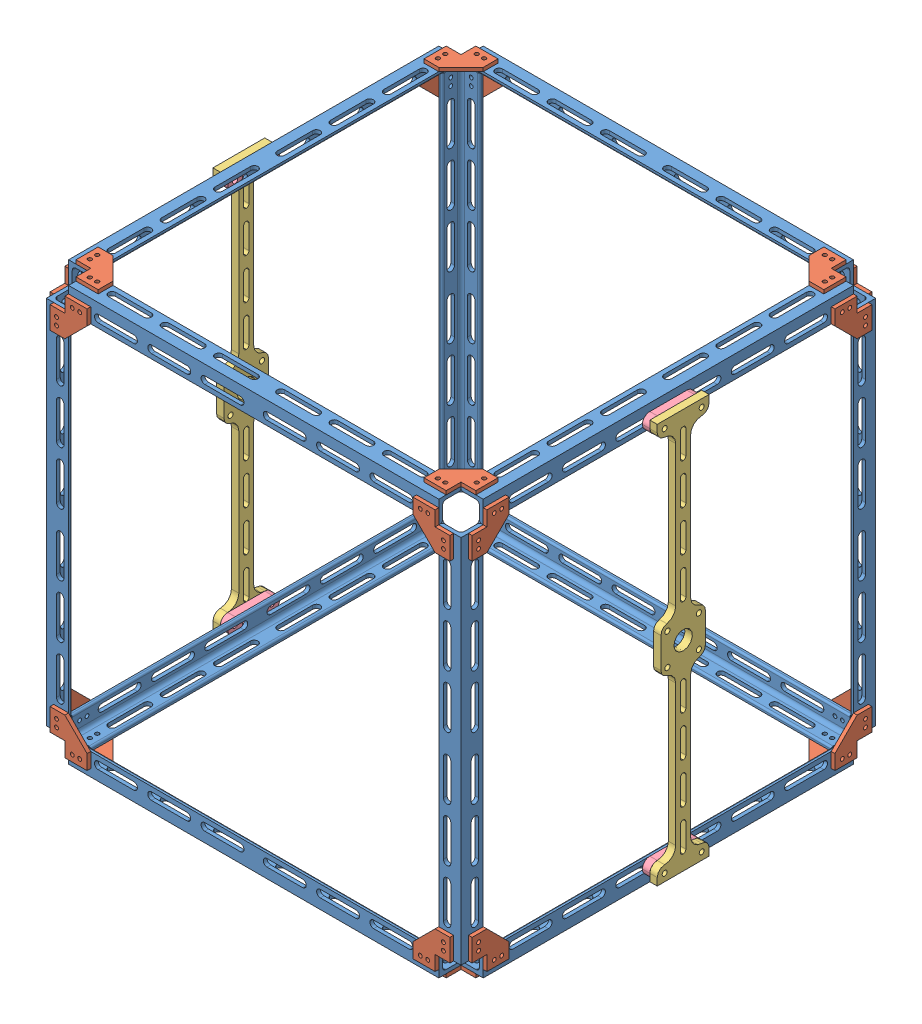
SolidWorks assembly Sattelite_BearingCrossbeams, configuration Default. Lengths in mm.
Overall size (381 361.95 361.95).
43 component instances, 4 part files, 6 mates.
Components (placement in the parent):
- Outer struct 14 in side length-1: Outer struct 14 in side length [Default] at (177.8 -177.8 0) size (361.95 361.95 361.95)
  - WIP 14 inch .75 L rod-1: WIP 14 inch .75 L rod [8982K281] at (-9.525 9.525 0) size (19.05 19.05 317.5)
  - WIP bracket for .75 L bar-1: WIP bracket for .75 L bar [Default] at (-44.45 -3.175 -171.45) size (31.75 3.17 31.75)
  - WIP 14 inch .75 L rod-2: WIP 14 inch .75 L rod [8982K281] at (-177.8 9.525 -168.275) x (0 0 -1) z (1 0 0) size (19.05 19.05 317.5)
  - WIP 14 inch .75 L rod-3: WIP 14 inch .75 L rod [8982K281] at (-9.525 177.8 -168.275) x (1 0 0) z (0 -1 0) size (19.05 19.05 317.5)
  - WIP bracket for .75 L bar-2: WIP bracket for .75 L bar [Default] at (0 44.45 -171.45) x (0 -1 0) z (0 0 1) size (31.75 3.17 31.75)
  - WIP bracket for .75 L bar-3: WIP bracket for .75 L bar [Default] at (-44.45 6.35 -177.8) x (1 0 0) z (0 1 0) size (31.75 3.17 31.75)
  - WIP bracket for .75 L bar-4: WIP bracket for .75 L bar [Default] at (-311.15 349.25 -177.8) x (-1 0 0) z (0 -1 0) size (31.75 3.17 31.75)
  - WIP bracket for .75 L bar-5: WIP bracket for .75 L bar [Default] at (-355.6 311.15 -171.45) x (0 1 0) z (0 0 1) size (31.75 3.17 31.75)
  - WIP bracket for .75 L bar-6: WIP bracket for .75 L bar [Default] at (-311.15 358.775 -171.45) x (-1 0 0) z (0 0 1) size (31.75 3.17 31.75)
  - WIP 14 inch .75 L rod-4: WIP 14 inch .75 L rod [8982K281] at (-177.8 346.075 -168.275) x (0 0 -1) z (-1 0 0) size (19.05 19.05 317.5)
  - WIP 14 inch .75 L rod-5: WIP 14 inch .75 L rod [8982K281] at (-346.075 346.075 0) x (-1 0 0) z (0 0 1) size (19.05 19.05 317.5)
  - WIP 14 inch .75 L rod-6: WIP 14 inch .75 L rod [8982K281] at (-346.075 177.8 -168.275) x (-1 0 0) z (0 1 0) size (19.05 19.05 317.5)
  - WIP bracket for .75 L bar-8: WIP bracket for .75 L bar [Default] at (-6.35 311.15 -177.8) x (0 1 0) z (-1 0 0) size (31.75 3.17 31.75)
  - WIP bracket for .75 L bar-9: WIP bracket for .75 L bar [Default] at (-349.25 44.45 -177.8) x (0 -1 0) z (1 0 0) size (31.75 3.17 31.75)
  - WIP bracket for .75 L bar-11: WIP bracket for .75 L bar [Default] at (-6.35 355.6 133.35) x (0 0 1) z (-1 0 0) size (31.75 3.17 31.75)
  - WIP bracket for .75 L bar-12: WIP bracket for .75 L bar [Default] at (-44.45 349.25 177.8) x (1 0 0) z (0 -1 0) size (31.75 3.17 31.75)
  - WIP 14 inch .75 L rod-7: WIP 14 inch .75 L rod [8982K281] at (-177.8 346.075 168.275) x (0 0 1) z (1 0 0) size (19.05 19.05 317.5)
  - WIP 14 inch .75 L rod-8: WIP 14 inch .75 L rod [8982K281] at (-9.525 346.075 0) x (0 1 0) z (0 0 1) size (19.05 19.05 317.5)
  - WIP bracket for .75 L bar-13: WIP bracket for .75 L bar [Default] at (3.175 349.25 133.35) x (0 0 1) z (0 -1 0) size (31.75 3.17 31.75)
  - WIP 14 inch .75 L rod-9: WIP 14 inch .75 L rod [8982K281] at (-9.525 177.8 168.275) x (0 0 1) z (0 -1 0) size (19.05 19.05 317.5)
  - WIP bracket for .75 L bar-14: WIP bracket for .75 L bar [Default] at (3.175 311.15 -171.45) x (0 1 0) z (0 0 1) size (31.75 3.17 31.75)
  - WIP bracket for .75 L bar-15: WIP bracket for .75 L bar [Default] at (-349.25 358.775 133.35) x (0 0 1) z (1 0 0) size (31.75 3.17 31.75)
  - WIP bracket for .75 L bar-16: WIP bracket for .75 L bar [Default] at (-44.45 355.6 -171.45) size (31.75 3.17 31.75)
  - WIP bracket for .75 L bar-17: WIP bracket for .75 L bar [Default] at (-6.35 -3.175 133.35) x (0 0 1) z (-1 0 0) size (31.75 3.17 31.75)
  - WIP bracket for .75 L bar-18: WIP bracket for .75 L bar [Default] at (3.175 44.45 171.45) x (0 -1 0) z (0 0 -1) size (31.75 3.17 31.75)
  - WIP bracket for .75 L bar-19: WIP bracket for .75 L bar [Default] at (-349.25 311.15 177.8) x (0 1 0) z (1 0 0) size (31.75 3.17 31.75)
  - WIP bracket for .75 L bar-20: WIP bracket for .75 L bar [Default] at (-355.6 349.25 133.35) x (0 0 1) z (0 -1 0) size (31.75 3.17 31.75)
  - WIP bracket for .75 L bar-21: WIP bracket for .75 L bar [Default] at (-355.6 44.45 171.45) x (0 -1 0) z (0 0 -1) size (31.75 3.17 31.75)
  - WIP 14 inch .75 L rod-11: WIP 14 inch .75 L rod [8982K281] at (-346.075 177.8 168.275) x (-1 0 0) z (0 -1 0) size (19.05 19.05 317.5)
  - WIP bracket for .75 L bar-22: WIP bracket for .75 L bar [Default] at (-311.15 6.35 177.8) x (-1 0 0) z (0 1 0) size (31.75 3.17 31.75)
  - WIP 14 inch .75 L rod-12: WIP 14 inch .75 L rod [8982K281] at (-177.8 9.525 168.275) x (0 0 1) z (-1 0 0) size (19.05 19.05 317.5)
  - WIP bracket for .75 L bar-23: WIP bracket for .75 L bar [Default] at (-311.15 -3.175 171.45) x (-1 0 0) z (0 0 -1) size (31.75 3.17 31.75)
  - WIP 14 inch .75 L rod-13: WIP 14 inch .75 L rod [8982K281] at (-346.075 9.525 0) x (-1 0 0) z (0 0 -1) size (19.05 19.05 317.5)
  - WIP bracket for .75 L bar-24: WIP bracket for .75 L bar [Default] at (-355.6 6.35 -133.35) x (0 0 -1) z (0 1 0) size (31.75 3.17 31.75)
  - WIP bracket for .75 L bar-25: WIP bracket for .75 L bar [Default] at (-349.25 -3.175 -133.35) x (0 0 -1) z (1 0 0) size (31.75 3.17 31.75)
  - WIP bracket for .75 L bar-26: WIP bracket for .75 L bar [Default] at (-6.35 44.45 177.8) x (0 -1 0) z (-1 0 0) size (31.75 3.17 31.75)
- Bearing_CrossBar-1: Bearing_CrossBar [Default] at (184.15 0 0) x (0 -1 0) z (1 0 0) size (342.9 44.45 6.35)
- Bearing_CrossBar_Spacer-1: Bearing_CrossBar_Spacer [Default] at (184.15 165.1 0) x (0 0 1) z (0 -1 0) size (44.45 6.35 12.7)
- Bearing_CrossBar_Spacer-2: Bearing_CrossBar_Spacer [Default] at (184.15 -165.1 0) x (0 0 1) z (0 -1 0) size (44.45 6.35 12.7)
- Bearing_CrossBar_Spacer-3: Bearing_CrossBar_Spacer [Default] at (-184.15 165.1 0) x (0 0 1) z (0 1 0) size (44.45 6.35 12.7)
- Bearing_CrossBar_Spacer-4: Bearing_CrossBar_Spacer [Default] at (-184.15 -165.1 0) x (0 0 1) z (0 1 0) size (44.45 6.35 12.7)
- Bearing_CrossBar-2: Bearing_CrossBar [Default] at (-190.5 0 0) x (0 -1 0) z (1 0 0) size (342.9 44.45 6.35)
Mates (geometry in assembly coordinates):
- Distance1: distance = 6.35 mm aligned: plane of Bearing_CrossBar-1 through (190.5 171.45 0) normal (0 1 0); plane of Outer struct 14 in side length-1/WIP 14 inch .75 L rod-8 through (177.8 177.8 158.75) normal (0 1 0)
- Coincident6: coincident: line of Bearing_CrossBar-1 through (184.15 0 0) axis (1 0 0)
- Concentric1: concentric anti-aligned: cylinder of Bearing_CrossBar-1 through (184.15 165.1 15.875) axis (1 0 0) radius 2.1526; cylinder of Bearing_CrossBar_Spacer-1 through (177.8 165.1 15.875) axis (-1 0 0) radius 2.1526
- Coincident7: coincident anti-aligned: plane of Bearing_CrossBar-1 through (184.15 0 0) normal (-1 0 0); plane of Bearing_CrossBar_Spacer-1 through (184.15 165.1 0) normal (1 0 0)
- Coincident8: coincident anti-aligned: plane of Outer struct 14 in side length-1/WIP 14 inch .75 L rod-8 through (177.8 158.75 158.75) normal (1 0 0); plane of Bearing_CrossBar_Spacer-1 through (177.8 165.1 0) normal (-1 0 0)
- Concentric2: concentric anti-aligned: cylinder of Bearing_CrossBar-1 through (184.15 165.1 -15.875) axis (1 0 0) radius 2.1526; cylinder of Bearing_CrossBar_Spacer-1 through (177.8 165.1 -15.875) axis (-1 0 0) radius 2.1526
